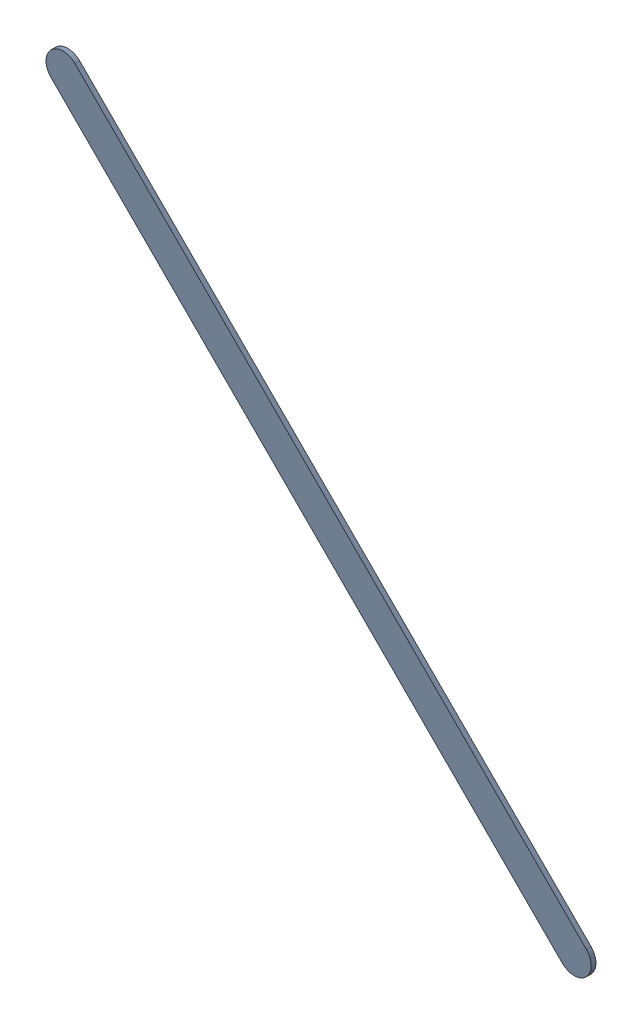
SolidWorks assembly Track (20.574mm,53.426mm)(24.4mm,49.6mm) on Bottom Layer, configuration Predeterminado. Lengths in mm.
Overall size (4.08 4.08 0.04).
2 component instances, 1 part files, 0 mates.
Components (placement in the parent):
- Track (20.574mm,53.426mm)(24.4mm,49.6mm) on Bottom Layer-1-1: Track (20.574mm,53.426mm)(24.4mm,49.6mm) on Bottom Layer-1 [Predeterminado] at (-68.317 -44.187 -0.4013) size (4.08 4.08 0.04)
  - Track (20.574mm,53.426mm)(24.4mm,49.6mm) on Bottom Layer-Part-1-1: Track (20.574mm,53.426mm)(24.4mm,49.6mm) on Bottom Layer-Part-1 [Predeterminado] at origin size (4.08 4.08 0.04)
